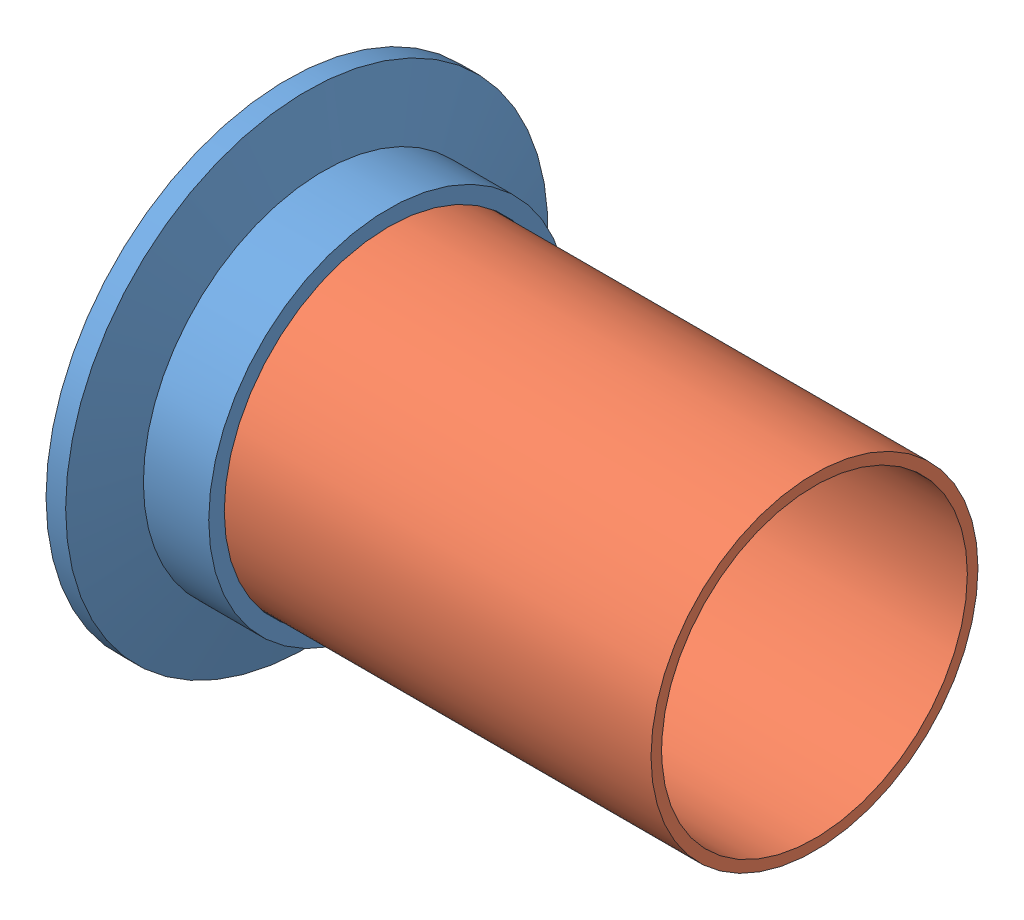
SolidWorks assembly 720004, configuration Default. Lengths in mm.
Overall size (81.92 74.93 74.93).
2 component instances, 2 part files, 2 mates.
Components (placement in the parent):
- 713004-1: 713004 [Default] at (26.461 37.9584 54.9335) size (15.75 74.93 74.93)
- 940103-1: 940103 [Default] at (108.376 37.9584 54.9335) x (0 0 1) z (-1 0 0) size (50.8 50.8 76.2)
Mates (geometry in assembly coordinates):
- Coincident1: coincident: plane of 713004-1 through (32.176 63.4854 54.9335) normal (1 0 0); plane of 940103-1 through (32.176 37.9584 54.9335) normal (-1 0 0)
- Concentric1: concentric anti-aligned: cylinder of 713004-1 through (26.461 37.9584 54.9335) axis (-1 0 0) radius 27.94; cylinder of 940103-1 through (32.176 37.9584 54.9335) axis (1 0 0) radius 25.4
